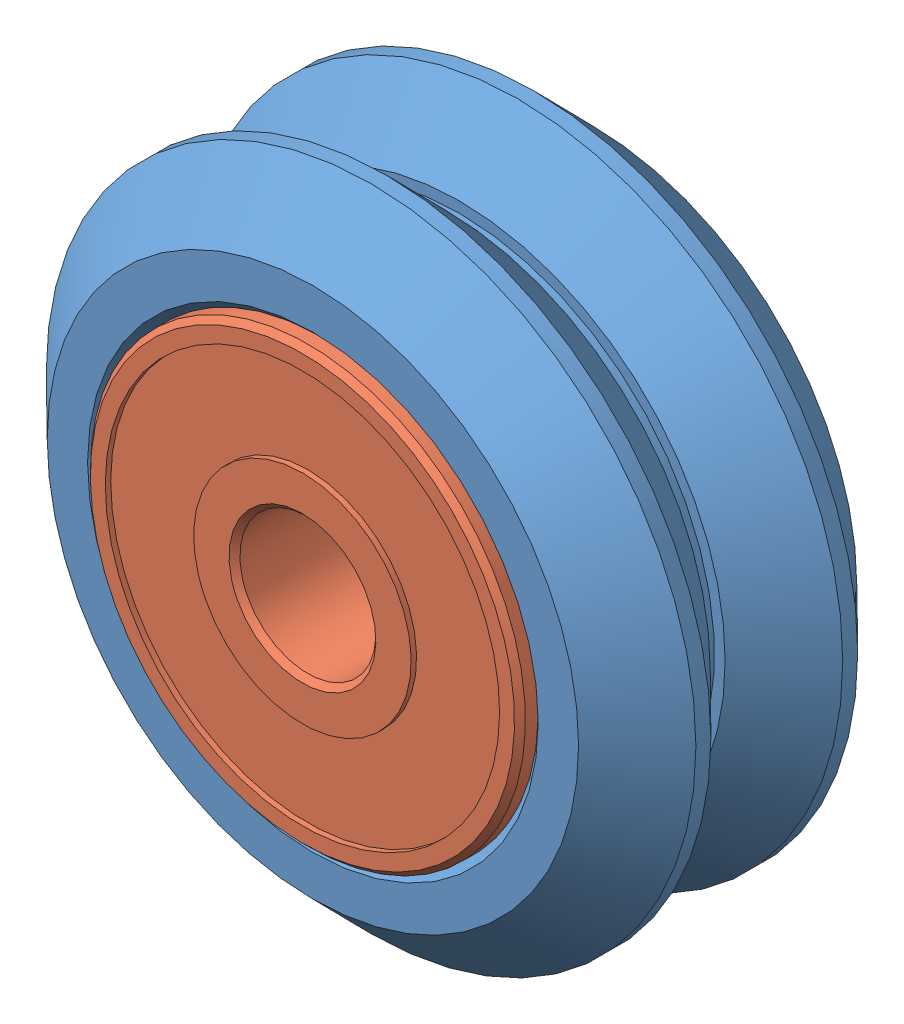
SolidWorks assembly Assem-Wheel set, configuration Default. Lengths in mm.
Overall size (23.89 23.89 11).
4 component instances, 3 part files, 6 mates.
Components (placement in the parent):
- part-openBuilds-Delrin Dual V-Wheel-1: part-openBuilds-Delrin Dual V-Wheel [Default] at (3.7783 11.4639 21.731) size (23.89 23.89 10.23)
- Precision Ball Bearing-1: Precision Ball Bearing [Default] at (3.7783 11.4639 18.731) x (0 0 -1) z (1 -0.000959 0) size (5 16 16)
- Precision Ball Bearing-2: Precision Ball Bearing [Default] at (3.7783 11.4639 24.731) x (0 0 -1) z (0.931116 0.364723 0) size (5 16 16)
- part-openBuilds-precision shim-1: part-openBuilds-precision shim [Default] at (3.7783 11.4639 21.731) x (-0.082647 -0.996579 0) z (0.996579 -0.082647 0) size (10 1 10)
Mates (geometry in assembly coordinates):
- Concentric1: concentric anti-aligned: cylinder of part-openBuilds-Delrin Dual V-Wheel-1 through (3.7783 11.4639 26.846) axis (0 0 1) radius 6.945; circle of part-openBuilds-precision shim-1
- Coincident1: coincident anti-aligned: plane of part-openBuilds-Delrin Dual V-Wheel-1 through (3.7783 11.4639 21.731) normal (0 0 1); plane of part-openBuilds-precision shim-1 through (3.7783 11.4639 21.731) normal (0 0 -1)
- Concentric2: concentric anti-aligned: circle of part-openBuilds-Delrin Dual V-Wheel-1; circle of Precision Ball Bearing-1
- Concentric3: concentric anti-aligned: circle of part-openBuilds-Delrin Dual V-Wheel-1; circle of Precision Ball Bearing-2
- Coincident2: coincident anti-aligned: plane of part-openBuilds-Delrin Dual V-Wheel-1 through (3.7783 19.4509 22.231) normal (0 0 1); plane of Precision Ball Bearing-2 through (3.7783 11.4639 22.231) normal (0 0 -1)
- Coincident3: coincident anti-aligned: plane of part-openBuilds-Delrin Dual V-Wheel-1 through (3.7783 19.4509 21.231) normal (0 0 -1); plane of Precision Ball Bearing-1 through (3.7783 11.4639 21.231) normal (0 0 1)
